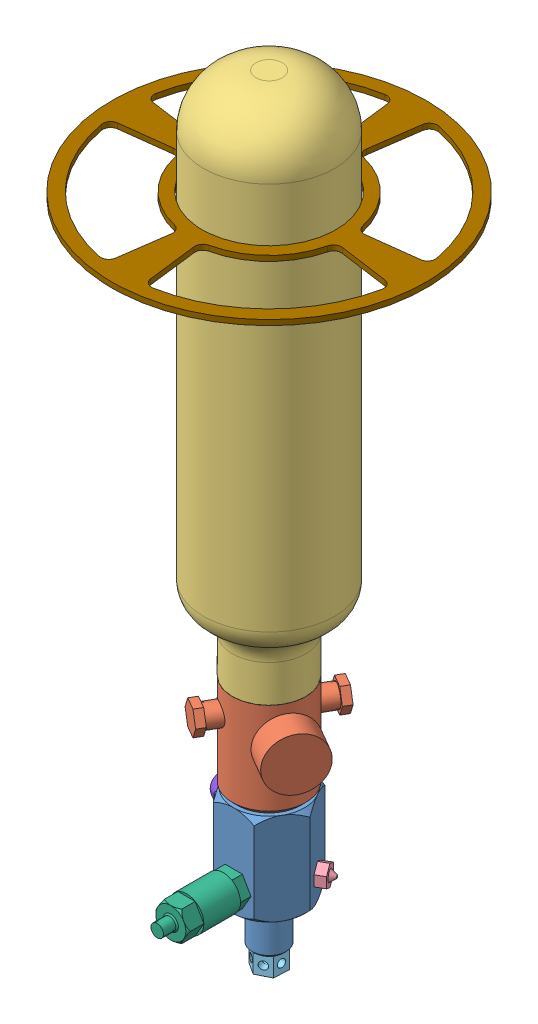
SolidWorks assembly SubSys_FuelPress, configuration Standard. Lengths in mm.
Overall size (120 296 120).
9 component instances, 9 part files, 19 mates.
Components (placement in the parent):
- P5_Fuel_press_Manifold-1: P5_Fuel_press_Manifold [Default] at (0 -17 0) size (34.29 52 27)
- P3_Press_Reg-1: P3_Press_Reg [Standard] at (0 292 0) x (0.866025 0 0.5) z (0.5 0 -0.866025) size (58.5 79.6 44)
- P1_Fuel_Press_Tank-1: P1_Fuel_Press_Tank [Standard] at (0 272 0) x (-0.962036 0 -0.272923) z (-0.272923 0 0.962036) size (50 200 50)
- P9_Bleed_Orifice-1: P9_Bleed_Orifice [Default] at (11.6913 9 -6.75) x (-0.435421 -0.491563 -0.754171) z (0.866025 0 -0.5) size (8.08 7 13)
- P78_Diffusor-1: P78_Diffusor [Standard] at (0 -7 0) x (-0.837169 0 -0.546944) z (-0.546944 0 0.837169) size (11.55 17 10)
- P8_Pressure_Sensor-1: P8_Pressure_Sensor [Default] at (0 9 13.5) x (0 0 1) z (-1 0 0) size (35.2 13.2 14.52)
- P10_G-1-4_USIT_FKM-1: P10_G-1-4_USIT_FKM [Default] at (0 -2 0) size (20.6 2 20.6)
- P6_Safety_Valve-1: P6_Safety_Valve [Default] at (-24.6817 9 -14.25) x (0.5 0 -0.866025) z (0.866025 0 0.5) size (16.08 18.56 34)
- P2_Fuel_Press_Tank_Centering_Ring-1: P2_Fuel_Press_Tank_Centering_Ring [Default] at (0 230 0) size (120 2 120)
Mates (geometry in assembly coordinates):
- Konzentrisch1: concentric: cylinder of P5_Fuel_press_Manifold-1 through (0 16 0) axis (0 1 0) radius 9.5
- Deckungsgleich2: coincident: plane of P5_Fuel_press_Manifold-1 through (0 0 0) normal (0 -1 0)
- Konzentrisch2: concentric aligned: cylinder of P5_Fuel_press_Manifold-1 through (0 16 0) axis (0 1 0) radius 9.5; cylinder of P3_Press_Reg-1 through (0 35 0) axis (0 1 0) radius 14
- Parallel1: parallel aligned: plane of P5_Fuel_press_Manifold-1 through (7.7942 35 13.5) normal (0.866025 0 0.5); plane of P3_Press_Reg-1 through (24.6817 62 14.25) normal (0.866025 0 0.5)
- Deckungsgleich4: coincident anti-aligned: plane of P5_Fuel_press_Manifold-1 through (0 35 0) normal (0 1 0); plane of P3_Press_Reg-1 through (0 35 0) normal (0 -1 0)
- Konzentrisch3: concentric aligned: cylinder of P3_Press_Reg-1 through (0 35 0) axis (0 1 0) radius 14; cylinder of P1_Fuel_Press_Tank-1 through (0 272 0) axis (0 1 0) radius 25
- Deckungsgleich5: coincident anti-aligned: plane of P3_Press_Reg-1 through (0 72 0) normal (0 1 0); plane of P1_Fuel_Press_Tank-1 through (-13.4685 72 -3.8209) normal (0 -1 0)
- Konzentrisch4: concentric anti-aligned: cylinder of P5_Fuel_press_Manifold-1 through (-17.5382 9 10.1257) axis (0.866025 0 -0.5) radius 2.5; cylinder of P9_Bleed_Orifice-1 through (11.6913 9 -6.75) axis (-0.866025 0 0.5) radius 2.942
- Deckungsgleich6: coincident anti-aligned: plane of P5_Fuel_press_Manifold-1 through (15.5885 35 0) normal (0.866025 0 -0.5); plane of P9_Bleed_Orifice-1 through (11.6913 9 -6.75) normal (-0.866025 0 0.5)
- Konzentrisch5: concentric anti-aligned: cylinder of P5_Fuel_press_Manifold-1 through (0 35.001 0) axis (0 -1 0) radius 3.4; cylinder of Diffusor_6kant-1 through (0 -17 0) axis (0 1 0) radius 3.935
- Deckungsgleich7: coincident anti-aligned: plane of P5_Fuel_press_Manifold-1 through (0 -17 0) normal (0 -1 0); plane of Diffusor_6kant-1 through (0 -17 0) normal (0 1 0)
- Konzentrisch6: concentric anti-aligned: cylinder of P5_Fuel_press_Manifold-1 through (0 9 -13.501) axis (0 0 1) radius 2.5; cylinder of P8_Pressure_Sensor-1 through (0 9 -12.6864) axis (0 0 -1) radius 3
- Deckungsgleich8: coincident anti-aligned: plane of P5_Fuel_press_Manifold-1 through (-7.7942 35 13.5) normal (0 0 1); plane of P8_Pressure_Sensor-1 through (6.6 9 13.5) normal (0 0 -1)
- Konzentrisch7: concentric aligned: cylinder of P5_Fuel_press_Manifold-1 through (0 -2 0) axis (0 -1 0) radius 6.5; cylinder of P10_G-1-4_USIT_FKM-1 through (0 0 0) axis (0 -1 0) radius 7
- Deckungsgleich9: coincident anti-aligned: plane of P5_Fuel_press_Manifold-1 through (0 0 0) normal (0 -1 0); plane of P10_G-1-4_USIT_FKM-1 through (0 0 0) normal (0 1 0)
- Konzentrisch8: concentric anti-aligned: cylinder of P5_Fuel_press_Manifold-1 through (-1.299 9 -0.75) axis (-0.866025 0 -0.5) radius 4.4; cylinder of P6_Safety_Valve-1 through (-5.9236 9 -3.42) axis (0.866025 0 0.5) radius 5
- Deckungsgleich10: coincident anti-aligned: plane of P5_Fuel_press_Manifold-1 through (-7.7942 35 -13.5) normal (-0.866025 0 -0.5); plane of P6_Safety_Valve-1 through (-7.2862 17.9142 -14.38) normal (0.866025 0 0.5)
- Konzentrisch9: concentric anti-aligned: cylinder of P1_Fuel_Press_Tank-1 through (0 272 0) axis (0 1 0) radius 25; cylinder of P2_Fuel_Press_Tank_Centering_Ring-1 through (0 232 0) axis (0 -1 0) radius 25.5
- Abstand1: distance = 40 mm aligned: plane of P2_Fuel_Press_Tank_Centering_Ring-1 through (0 232 0) normal (0 1 0); plane of P1_Fuel_Press_Tank-1 through (0 272 0) normal (0 1 0)
